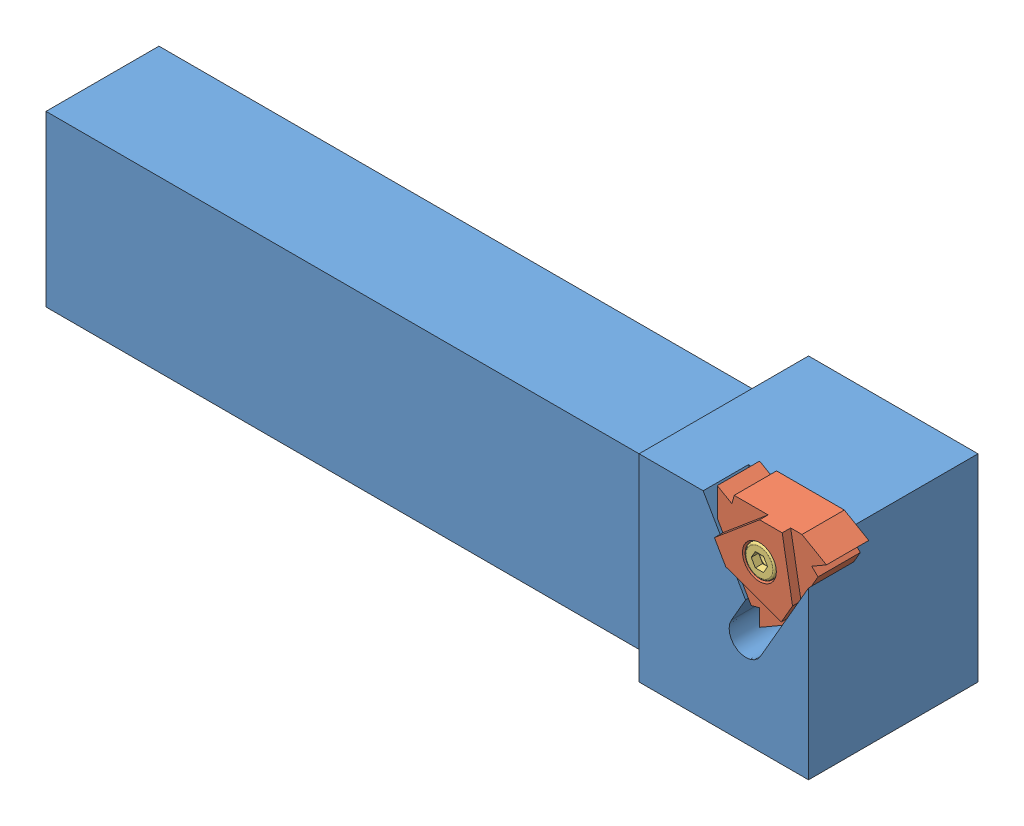
SolidWorks assembly 螺纹刀, configuration 默认. Lengths in mm.
Overall size (136.42 44.29 31).
3 component instances, 3 part files, 5 mates.
Components (placement in the parent):
- 螺纹刀刀柄-1: 螺纹刀刀柄 [默认] at (-16.4578 2.7309 -10) size (130 35 30)
- 螺纹刀刀片-4: 螺纹刀刀片 [默认] at (72.0821 -15.7156 7) x (0.5 -0.866025 0) z (0 0 1) size (19.33 17.99 9)
- hexagon socket head cap screws gb-1: hexagon socket head cap screws gb [GB_FASTENER_SCREWS_HSHCS M3X5-N] at (60.8427 17.7759 16) x (0 0 -1) z (1 0 0) size (8 5.5 5.5)
Mates (geometry in assembly coordinates):
- 重合1: coincident anti-aligned: plane of 螺纹刀刀柄-1 through (61.8983 5.6477 7) normal (-0.866025 0.5 0); plane of 螺纹刀刀片-4 through (63.7099 8.7855 16) normal (0.866025 -0.5 0)
- 重合2: coincident anti-aligned: plane of 螺纹刀刀柄-1 through (57.385 9.7405 7) normal (0.866025 0.5 0); plane of 螺纹刀刀片-4 through (51.8798 19.2759 16) normal (-0.866025 -0.5 0)
- 重合3: coincident anti-aligned: plane of 螺纹刀刀柄-1 through (57.4636 3.9216 7) normal (0 0 1); plane of 螺纹刀刀片-4 through (72.0821 -15.7156 7) normal (0 0 -1)
- 同心1: concentric aligned: cylinder of 螺纹刀刀片-4 through (60.8427 17.7759 16) axis (0 0 1) radius 1.5; cylinder of hexagon socket head cap screws gb-1 through (60.8427 17.7759 8) axis (0 0 1) radius 1.5
- 重合4: coincident anti-aligned: plane of 螺纹刀刀片-4 through (61.5927 16.4768 13) normal (0 0 1); plane of hexagon socket head cap screws gb-1 through (60.8427 17.7759 13) normal (0 0 -1)
